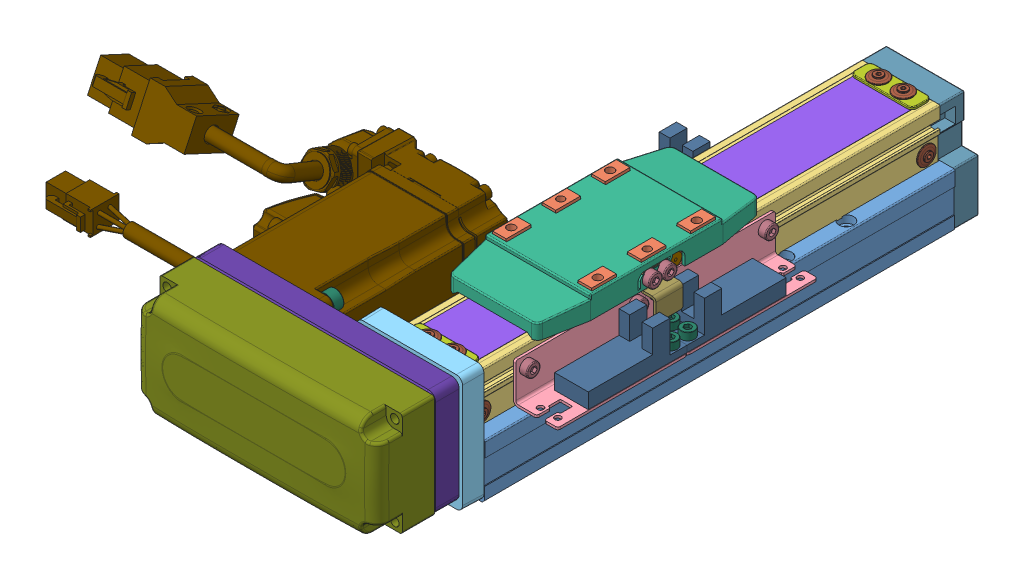
SolidWorks assembly G4-BR-100W, configuration 默认. Lengths in mm.
Overall size (192.63 57.84 250).
59 component instances, 18 part files, 58 mates.
Components (placement in the parent):
- 复件 底座GY4+140^G4-BR-100W-1: 复件 底座GY4+140^G4-BR-100W [默认] at (-6.4941 12.4482 0) x (-1 0 0) z (0 -1 0) size (44 190 22.05) (virtual)
- 复件 滑台G4^G4-BR-100W-1: 复件 滑台G4^G4-BR-100W [默认] at (2.1217 9 -70) x (-1 0 0) z (0 0 -1) size (40 11.99 50) (virtual)
- 复件 侧盖G4+140^G4-BR-100W-1: 复件 侧盖G4+140^G4-BR-100W [默认] at (5.1767 14.25 0) x (-1 0 0) z (0 0 -1) size (8.3 20.5 190) (virtual)
- 复件 304开关座片G5-12^G4-BR-100W-1: 复件 304开关座片G5-12^G4-BR-100W [Default] at (5.9767 22.8 -17.5) x (0 0 -1) z (1 0 0) size (52.5 16 18) (virtual)
- 复件 丝杆座板GY4^G4-BR-100W-1: 复件 丝杆座板GY4^G4-BR-100W [默认] at (-9.9033 24.8518 0) x (-1 0 0) z (0 0 -1) size (43 47.4 8.5) (virtual)
- 复件 滑台盖G4^G4-BR-100W-1: 复件 滑台盖G4^G4-BR-100W [默认] at (-9.9033 42.1 -115) x (0 0 1) z (0 -1 0) size (90 42.6 9) (virtual)
- 复件 304钢带压片G4^G4-BR-100W-1: 复件 304钢带压片G4^G4-BR-100W [默认] at (-9.9033 41.6 -186) x (-1 0 0) z (0 0 -1) size (25 1 8) (virtual)
- 复件 钢带G4+140^G4-BR-100W-1: 复件 钢带G4+140^G4-BR-100W [Default] at (-20.8433 41.5 -581.114) x (0 0 -1) z (0 1 0) size (190 23.5 0.1) (virtual)
- 复件 304钢带压片G4^G4-BR-100W-2: 复件 304钢带压片G4^G4-BR-100W [默认] at (-9.9033 41.6 -4) x (-1 0 0) z (0 0 -1) size (25 1 8) (virtual)
- 复件 弹子油杯D5x5.5^G4-BR-100W-1: 复件 弹子油杯D5x5.5^G4-BR-100W [默认] at (-30.3783 45.5 -78.5) x (0 0.72753 0.686076) z (1 0 0) size (5 5 5.73) (virtual)
- 复件 弹子油杯D5x5.5^G4-BR-100W-2: 复件 弹子油杯D5x5.5^G4-BR-100W [默认] at (10.6217 45.5 -78.5) x (0 0.972647 -0.232289) z (-1 0 0) size (5 5 5.73) (virtual)
- 复件 光电开关EE-SX674^G4-BR-100W-1: 复件 光电开关EE-SX674^G4-BR-100W [默认] at (10.1767 23.8 -30) x (0 0 -1) z (1 0 0) size (40 15.5 13.6) (virtual)
- 复件 不锈钢内六角定制螺丝M3X7^G4-BR-100W-1: 复件 不锈钢内六角定制螺丝M3X7^G4-BR-100W [默认] at (-4.9033 42.9733 -4) x (0.724639 0 -0.689128) z (0 -1 0) size (7.67 7.67 6.5) (virtual)
- 复件 不锈钢内六角定制螺丝M3X7^G4-BR-100W-2: 复件 不锈钢内六角定制螺丝M3X7^G4-BR-100W [默认] at (-14.9033 42.9733 -4) x (0.264221 0 -0.964462) z (0 -1 0) size (7.67 7.67 6.5) (virtual)
- 复件 不锈钢内六角定制螺丝M3X7^G4-BR-100W-3: 复件 不锈钢内六角定制螺丝M3X7^G4-BR-100W [默认] at (-4.9033 42.9733 -186) x (-0.045987 0 0.998942) z (0 -1 0) size (7.67 7.67 6.5) (virtual)
- 复件 不锈钢内六角定制螺丝M3X7^G4-BR-100W-4: 复件 不锈钢内六角定制螺丝M3X7^G4-BR-100W [默认] at (-14.9033 42.9733 -186) x (0.70866 0 0.705551) z (0 -1 0) size (7.67 7.67 6.5) (virtual)
- 复件 不锈钢内六角定制螺丝M3X7^G4-BR-100W-5: 复件 不锈钢内六角定制螺丝M3X7^G4-BR-100W [默认] at (5.55 26.15 -5) x (0 0.645926 0.7634) z (-1 0 0) size (7.67 7.67 6.5) (virtual)
- 复件 不锈钢内六角定制螺丝M3X7^G4-BR-100W-6: 复件 不锈钢内六角定制螺丝M3X7^G4-BR-100W [默认] at (5.55 26.15 -185) x (0 0.430934 0.902383) z (-1 0 0) size (7.67 7.67 6.5) (virtual)
- 复件 不锈钢内六角定制螺丝M3X7^G4-BR-100W-7: 复件 不锈钢内六角定制螺丝M3X7^G4-BR-100W [默认] at (-25.3602 26.15 -185) x (0 -0.999999 -0.001479) z (1 0 0) size (7.67 7.67 6.5) (virtual)
- 复件 不锈钢内六角定制螺丝M3X7^G4-BR-100W-8: 复件 不锈钢内六角定制螺丝M3X7^G4-BR-100W [默认] at (-25.3565 26.15 -5) x (0 -1 0) z (1 0 0) size (7.67 7.67 6.5) (virtual)
- 复件 304感应片G5^G4-BR-100W-1: 复件 304感应片G5^G4-BR-100W [默认] at (15.6217 33 -75.5) x (0 1 0) z (0 0 1) size (15 6.5 11) (virtual)
- hexagon socket head cap screws gb-32: hexagon socket head cap screws gb [GB_FASTENER_SCREWS_HSHCS M3X6-N] at (14.1217 45.5 -73) x (-1 0 0) z (0 -0.928252 -0.371951) size (9 5.5 5.5)
- 复件 光电开关EE-SX674^G4-BR-100W-15: 复件 光电开关EE-SX674^G4-BR-100W [默认] at (23.7767 23.8 -110) x (0 0 1) z (-1 0 0) size (40 15.5 13.6) (virtual)
- 复件 304开关座片G5-12^G4-BR-100W-11: 复件 304开关座片G5-12^G4-BR-100W [Default] at (5.9767 22.8 -70) x (0 0 -1) z (1 0 0) size (52.5 16 18) (virtual)
- 复件 304开关座片G5-12^G4-BR-100W-10: 复件 304开关座片G5-12^G4-BR-100W [Default] at (5.9767 22.8 -87.5) x (0 0 -1) z (1 0 0) size (52.5 16 18) (hidden, virtual)
- 复件 轴承端盖G4(机加件)^G4-BR-100W-1: 复件 轴承端盖G4(机加件)^G4-BR-100W [默认] at (-9.9033 11.9 -190) x (0 0 -1) z (1 0 0) size (10 40.8 43) (virtual)
- hexagon socket head cap screws gb-33: hexagon socket head cap screws gb [GB_FASTENER_SCREWS_HSHCS M3X6-N] at (14.1217 45.5 -67) x (-1 0 0) z (0 -0.928252 -0.371951) size (9 5.5 5.5)
- hexagon socket head cap screws gb-34: hexagon socket head cap screws gb [GB_FASTENER_SCREWS_HSHCS M3X6-N] at (-33.8783 45.5 -73) x (1 0 0) z (0 0.928252 0.371951) size (9 5.5 5.5)
- hexagon socket head cap screws gb-35: hexagon socket head cap screws gb [GB_FASTENER_SCREWS_HSHCS M3X6-N] at (-33.8783 45.5 -67) x (1 0 0) z (0 0.928252 0.371951) size (9 5.5 5.5)
- 复件 侧盖G4+140^G4-BR-100W-5: 复件 侧盖G4+140^G4-BR-100W [默认] at (-24.9833 14.25 -190) size (8.3 20.5 190) (virtual)
- 复件 光电开关EE-SX674^G4-BR-100W-14: 复件 光电开关EE-SX674^G4-BR-100W [默认] at (10.1767 23.8 -100) x (0 0 -1) z (1 0 0) size (40 15.5 13.6) (hidden, virtual)
- 复件 光电开关EE-SX674^G4-BR-100W-16: 复件 光电开关EE-SX674^G4-BR-100W [默认] at (-43.5833 23.8 -100) x (0 0 -1) z (1 0 0) size (40 15.5 13.6) (virtual)
- 复件 304开关座片G5-12^G4-BR-100W-14: 复件 304开关座片G5-12^G4-BR-100W [Default] at (-25.7833 22.8 -140) x (0 0 1) z (-1 0 0) size (52.5 16 18) (virtual)
- 复件 304感应片G5^G4-BR-100W-4: 复件 304感应片G5^G4-BR-100W [默认] at (-35.3783 33 -64.5) x (0 1 0) z (0 0 -1) size (15 6.5 11) (virtual)
- hexagon socket head cap screws gb-36: hexagon socket head cap screws gb [GB_FASTENER_SCREWS_HSHCS M3X6-N] at (-26.4033 5.05 -199.6) x (0 0 1) z (-0.891634 -0.452757 0) size (9 5.5 5.5)
- hexagon socket head cap screws gb-37: hexagon socket head cap screws gb [GB_FASTENER_SCREWS_HSHCS M3X6-N] at (6.5967 5.05 -199.6) x (0 0 1) z (-0.891634 -0.452757 0) size (9 5.5 5.5)
- hexagon socket head cap screws gb-38: hexagon socket head cap screws gb [GB_FASTENER_SCREWS_HSHCS M3X6-N] at (-26.4033 18.05 -199.6) x (0 0 1) z (-0.891634 -0.452757 0) size (9 5.5 5.5)
- hexagon socket head cap screws gb-39: hexagon socket head cap screws gb [GB_FASTENER_SCREWS_HSHCS M3X6-N] at (6.5967 18.05 -199.6) x (0 0 1) z (-0.891634 -0.452757 0) size (9 5.5 5.5)
- hexagon socket head cap screws gb-41: hexagon socket head cap screws gb [GB_FASTENER_SCREWS_HSHCS M3X6-N] at (9.9767 34.8 -21.75) x (-1 0 0) z (0 -0.928252 -0.371951) size (9 5.5 5.5)
- hexagon socket head cap screws gb-42: hexagon socket head cap screws gb [GB_FASTENER_SCREWS_HSHCS M3X6-N] at (9.9767 34.8 -65.75) x (-1 0 0) z (0 -0.928252 -0.371951) size (9 5.5 5.5)
- hexagon socket head cap screws gb-43: hexagon socket head cap screws gb [GB_FASTENER_SCREWS_HSHCS M3X6-N] at (9.9767 34.8 -74.25) x (-1 0 0) z (0 0.928252 -0.371951) size (9 5.5 5.5)
- hexagon socket head cap screws gb-44: hexagon socket head cap screws gb [GB_FASTENER_SCREWS_HSHCS M3X6-N] at (9.9767 34.8 -118.25) x (-1 0 0) z (0 0.928252 -0.371951) size (9 5.5 5.5)
- hexagon socket head cap screws gb-45: hexagon socket head cap screws gb [GB_FASTENER_SCREWS_HSHCS M3X6-N] at (9.9767 34.8 -91.75) x (-1 0 0) z (0 -0.928252 -0.371951) size (9 5.5 5.5) (hidden)
- hexagon socket head cap screws gb-46: hexagon socket head cap screws gb [GB_FASTENER_SCREWS_HSHCS M3X6-N] at (9.9767 34.8 -135.75) x (-1 0 0) z (0 -0.928252 -0.371951) size (9 5.5 5.5) (hidden)
- hexagon socket head cap screws gb-47: hexagon socket head cap screws gb [GB_FASTENER_SCREWS_HSHCS M3X6-N] at (-29.7833 34.8 -135.75) x (1 0 0) z (0 0.928252 0.371951) size (9 5.5 5.5)
- hexagon socket head cap screws gb-48: hexagon socket head cap screws gb [GB_FASTENER_SCREWS_HSHCS M3X6-N] at (-29.7833 34.8 -91.75) x (1 0 0) z (0 0.928252 0.371951) size (9 5.5 5.5)
- socket head cap screw_iso-2: socket head cap screw_iso [ISO 4762 M3 x 5 --- 5N] at (13.4767 29.4 -66.5) x (0 -1 0) z (0 0 1) size (8 5.5 5.5)
- socket head cap screw_iso-3: socket head cap screw_iso [ISO 4762 M3 x 5 --- 5N] at (20.4767 29.4 -66.5) x (0 -1 0) z (0 0 1) size (8 5.5 5.5)
- socket head cap screw_iso-5: socket head cap screw_iso [ISO 4762 M4 x 12 --- 12N] at (-48.8898 41.2635 -0.5) x (0 0 1) z (-0.923728 -0.383049 0) size (16 7 7)
- socket head cap screw_iso-6: socket head cap screw_iso [ISO 4762 M4 x 12 --- 12N] at (-81.4167 8.7365 -0.5) x (0 0 1) z (-0.988061 -0.154063 0) size (16 7 7)
- socket head cap screw_iso-7: socket head cap screw_iso [ISO 4762 M3 x 5 --- 5N] at (20.4767 29.4 -73.5) x (0 -1 0) z (0 0 1) size (8 5.5 5.5)
- socket head cap screw_iso-8: socket head cap screw_iso [ISO 4762 M3 x 5 --- 5N] at (13.4767 29.4 -73.5) x (0 -1 0) z (0 0 1) size (8 5.5 5.5)
- socket head cap screw_iso-9: socket head cap screw_iso [ISO 4762 M3 x 5 --- 5N] at (13.4767 29.4 -136.5) x (0 -1 0) z (0 0 1) size (8 5.5 5.5) (hidden)
- socket head cap screw_iso-10: socket head cap screw_iso [ISO 4762 M3 x 5 --- 5N] at (20.4767 29.4 -136.5) x (0 -1 0) z (0 0 1) size (8 5.5 5.5) (hidden)
- socket head cap screw_iso-11: socket head cap screw_iso [ISO 4762 M3 x 5 --- 5N] at (-33.2833 29.4 -136.5) x (0 -1 0) z (0 0 -1) size (8 5.5 5.5)
- socket head cap screw_iso-12: socket head cap screw_iso [ISO 4762 M3 x 5 --- 5N] at (-40.2833 29.4 -136.5) x (0 -1 0) z (0 0 -1) size (8 5.5 5.5)
- 复件 同步轮罩壳G4^G4-BR-100W-1: 复件 同步轮罩壳G4^G4-BR-100W [默认] at (-38.9033 25 41.5) x (1 0 0) z (0 1 0) size (98.56 24.45 42.56) (virtual)
- 复件 电机板G4-BLRM-P38^G4-BR-100W-1: 复件 电机板G4-BLRM-P38^G4-BR-100W [Default] at (-38.9033 25 -4.5) x (0 0 -1) z (0 -1 0) size (10 98 43) (virtual)
- 复件 台达100W电机ECM-B3L-C20401RS1^G4-BR-100W-1: 复件 台达100W电机ECM-B3L-C20401RS1^G4-BR-100W [Default] at (-65.1533 25 3.5) x (0 1 0) z (0 0 1) size (53.15 124.71 102.71) (virtual)
Mates (geometry in assembly coordinates):
- 重合86: coincident: plane of 复件 滑台G4^G4-BR-100W-1 through (-29.8783 50 -55) normal (0 1 0); plane of 复件 滑台盖G4^G4-BR-100W-1 through (-31.2033 50 -96.25) normal (0 -1 0)
- 同心50: concentric: cylinder of 复件 滑台G4^G4-BR-100W-1 through (-29.8783 45.5 -78.5) axis (-1 0 0) radius 2.5; cylinder of 复件 弹子油杯D5x5.5^G4-BR-100W-1 through (-24.8783 45.5 -78.5) axis (-1 0 0) radius 2.5
- 重合98: coincident: plane of 复件 滑台G4^G4-BR-100W-1 through (-24.8783 45.5 -78.5) normal (-1 0 0); circle of 复件 弹子油杯D5x5.5^G4-BR-100W-1
- 同心51: concentric: cylinder of 复件 滑台G4^G4-BR-100W-1 through (10.1217 45.5 -78.5) axis (1 0 0) radius 2.5; cylinder of 复件 弹子油杯D5x5.5^G4-BR-100W-2 through (5.1217 45.5 -78.5) axis (1 0 0) radius 2.5
- 重合99: coincident: plane of 复件 滑台G4^G4-BR-100W-1 through (5.1217 45.5 -78.5) normal (1 0 0); circle of 复件 弹子油杯D5x5.5^G4-BR-100W-2
- 重合127: coincident: plane of 复件 304钢带压片G4^G4-BR-100W-1 through (0.5967 42.6 -184) normal (0 1 0); circle of 复件 不锈钢内六角定制螺丝M3X7^G4-BR-100W-3
- 重合128: coincident: plane of 复件 304钢带压片G4^G4-BR-100W-1 through (0.5967 42.6 -184) normal (0 1 0); circle of 复件 不锈钢内六角定制螺丝M3X7^G4-BR-100W-4
- 同心86: concentric: circle of 复件 侧盖G4+140^G4-BR-100W-1; cylinder of 复件 不锈钢内六角定制螺丝M3X7^G4-BR-100W-6 through (0.07 26.15 -185) axis (1 0 0) radius 1.5
- 重合133: coincident: plane of 复件 侧盖G4+140^G4-BR-100W-1 through (5.1767 30.4257 -190) normal (1 0 0); circle of 复件 不锈钢内六角定制螺丝M3X7^G4-BR-100W-6
- 重合150: coincident: plane of 复件 滑台G4^G4-BR-100W-1 through (10.1217 42.5 -95) normal (1 0 0); plane of 复件 304感应片G5^G4-BR-100W-1 through (10.1217 41 -64.5) normal (-1 0 0)
- 同心103: concentric: cylinder of 复件 滑台G4^G4-BR-100W-1 through (10.1217 45.5 -73) axis (1 0 0) radius 1.25; cylinder of 复件 304感应片G5^G4-BR-100W-1 through (10.1217 45.5 -73) axis (-1 0 0) radius 1.7
- 同心104: concentric: cylinder of 复件 滑台G4^G4-BR-100W-1 through (10.1217 45.5 -67) axis (1 0 0) radius 1.25; cylinder of 复件 304感应片G5^G4-BR-100W-1 through (10.1217 45.5 -67) axis (-1 0 0) radius 1.7
- 同心105: concentric: cylinder of 复件 滑台G4^G4-BR-100W-1 through (10.1217 45.5 -73) axis (1 0 0) radius 1.25; cylinder of hexagon socket head cap screws gb-32 through (5.1217 45.5 -73) axis (1 0 0) radius 1.5
- 重合154: coincident: plane of 复件 304感应片G5^G4-BR-100W-1 through (11.1217 41 -64.5) normal (1 0 0); plane of hexagon socket head cap screws gb-32 through (11.1217 45.5 -73) normal (-1 0 0)
- 宽度8: width: plane of 复件 滑台盖G4^G4-BR-100W-1 through (-30.1033 42.1 -75.05) normal (0 0 1); plane of 复件 滑台盖G4^G4-BR-100W-1 through (-30.1033 42.1 -64.95) normal (0 0 -1); plane of 复件 滑台G4^G4-BR-100W-1 through (-29.8783 52 -65) normal (0 0 1); plane of 复件 滑台G4^G4-BR-100W-1 through (-29.8783 52 -75) normal (0 0 -1)
- 宽度9: width: plane of 复件 滑台G4^G4-BR-100W-1 through (-24.3783 48 -95) normal (1 0 0); plane of 复件 滑台G4^G4-BR-100W-1 through (-29.8783 52 -95) normal (-1 0 0); plane of 复件 滑台盖G4^G4-BR-100W-1 through (-24.1533 42.1 -64.95) normal (-1 0 0); plane of 复件 滑台盖G4^G4-BR-100W-1 through (-30.1033 50.6 -96.25) normal (1 0 0)
- 重合171: coincident: plane of 复件 底座GY4+140^G4-BR-100W-1 through (-31.4033 21.55 -190) normal (0 0 -1); plane of 复件 轴承端盖G4(机加件)^G4-BR-100W-1 through (-9.9033 11.9 -190) normal (0 0 1)
- 宽度10: width: plane of 复件 底座GY4+140^G4-BR-100W-1 through (12.0967 21.55 -190) normal (1 0 0); plane of 复件 底座GY4+140^G4-BR-100W-1 through (-31.9033 16.05 -190) normal (-1 0 0); plane of 复件 滑台盖G4^G4-BR-100W-1 through (-31.2033 50.6 -96.25) normal (-1 0 0); plane of 复件 滑台盖G4^G4-BR-100W-1 through (11.3967 50.6 -96.25) normal (1 0 0)
- 距离4: distance = 52 mm: plane of 复件 滑台G4^G4-BR-100W-1 through (-24.3783 52 -95) normal (0 1 0); plane of 复件 底座GY4+140^G4-BR-100W-1 through (15.1408 0 0) normal (0 -1 0)
- 重合187: coincident: plane of 复件 底座GY4+140^G4-BR-100W-1 through (-31.4033 6.05 -190) normal (-1 0 0); plane of 复件 轴承端盖G4(机加件)^G4-BR-100W-1 through (-31.4033 11.9 -200) normal (-1 0 0)
- 同心117: concentric: cylinder of 复件 不锈钢内六角定制螺丝M3X7^G4-BR-100W-7 through (-19.8802 26.15 -185) axis (-1 0 0) radius 1.5; cylinder of 复件 侧盖G4+140^G4-BR-100W-5 through (-24.9833 26.15 -185) axis (-1 0 0) radius 1.5
- 相切3: tangent: torus of 复件 不锈钢内六角定制螺丝M3X7^G4-BR-100W-7; plane of 复件 侧盖G4+140^G4-BR-100W-5 through (-24.9833 30.4257 0) normal (-1 0 0)
- 重合189: coincident: plane of 复件 304钢带压片G4^G4-BR-100W-1 through (0.5967 41.6 -184) normal (0 -1 0); plane of 复件 钢带G4+140^G4-BR-100W-1 through (-20.8433 41.6 -581.114) normal (0 1 0)
- 同心118: concentric: cylinder of 复件 304钢带压片G4^G4-BR-100W-1 through (-4.9033 42.6 -186) axis (0 -1 0) radius 1.65; cylinder of 复件 不锈钢内六角定制螺丝M3X7^G4-BR-100W-3 through (-4.9033 37.4933 -186) axis (0 1 0) radius 1.5
- 同心119: concentric: cylinder of 复件 304钢带压片G4^G4-BR-100W-1 through (-14.9033 42.6 -186) axis (0 -1 0) radius 1.65; cylinder of 复件 不锈钢内六角定制螺丝M3X7^G4-BR-100W-4 through (-14.9033 37.4933 -186) axis (0 1 0) radius 1.5
- 重合190: coincident: plane of 复件 304钢带压片G4^G4-BR-100W-1 through (0.5967 42.6 -190) normal (0 0 -1); plane of 复件 轴承端盖G4(机加件)^G4-BR-100W-1 through (-9.9033 11.9 -190) normal (0 0 1)
- 宽度11: width: plane of 复件 304钢带压片G4^G4-BR-100W-1 through (-22.4033 42.6 -184) normal (-1 0 0); plane of 复件 304钢带压片G4^G4-BR-100W-1 through (2.5967 42.6 -184) normal (1 0 0); plane of 复件 侧盖G4+140^G4-BR-100W-1 through (5.9767 41.05 -190) normal (1 0 0); plane of 复件 侧盖G4+140^G4-BR-100W-5 through (-25.7833 41.05 0) normal (-1 0 0)
- 重合191: coincident: plane of 复件 轴承端盖G4(机加件)^G4-BR-100W-1 through (-26.4033 6.75 -196.6) normal (0 0 -1); plane of hexagon socket head cap screws gb-36 through (-26.4033 5.05 -196.6) normal (0 0 1)
- 同心121: concentric: cylinder of 复件 轴承端盖G4(机加件)^G4-BR-100W-1 through (-26.4033 5.05 -200) axis (0 0 -1) radius 1.7; cylinder of hexagon socket head cap screws gb-36 through (-26.4033 5.05 -190.6) axis (0 0 -1) radius 1.5
- 重合193: coincident: plane of 复件 304开关座片G5-12^G4-BR-100W-1 through (6.9767 40.8 -70) normal (1 0 0); plane of hexagon socket head cap screws gb-41 through (6.9767 34.8 -21.75) normal (-1 0 0)
- 同心123: concentric: cylinder of 复件 304开关座片G5-12^G4-BR-100W-1 through (5.9767 34.8 -21.75) axis (1 0 0) radius 1.6; cylinder of hexagon socket head cap screws gb-41 through (0.9767 34.8 -21.75) axis (1 0 0) radius 1.5
- 同心126: concentric: cylinder of 复件 光电开关EE-SX674^G4-BR-100W-1 through (13.4767 12.8 -66.5) axis (0 1 0) radius 1.75; cylinder of socket head cap screw_iso-2 through (13.4767 61.15 -66.5) axis (0 1 0) radius 2.75
- 重合196: coincident: plane of 复件 光电开关EE-SX674^G4-BR-100W-1 through (23.7767 26.4 -63) normal (0 1 0); plane of socket head cap screw_iso-2 through (16.2267 26.4 -66.5) normal (0 -1 0)
- 同心127: concentric: cylinder of 复件 光电开关EE-SX674^G4-BR-100W-1 through (20.4767 12.8 -66.5) axis (0 1 0) radius 1.75; cylinder of socket head cap screw_iso-3 through (20.4767 61.15 -66.5) axis (0 1 0) radius 2.75
- 重合197: coincident: plane of 复件 光电开关EE-SX674^G4-BR-100W-1 through (23.7767 26.4 -63) normal (0 1 0); plane of socket head cap screw_iso-3 through (23.2267 26.4 -66.5) normal (0 -1 0)
- 重合198: coincident: plane of 复件 丝杆座板GY4^G4-BR-100W-1 through (-9.9033 24.8518 8.5) normal (0 0 1); plane of 复件 电机板G4-BLRM-P38^G4-BR-100W-1 through (-38.9033 25 8.5) normal (0 0 -1)
- 重合199: coincident: plane of 复件 同步轮罩壳G4^G4-BR-100W-1 through (-38.9033 25 18.5) normal (0 0 -1); plane of 复件 电机板G4-BLRM-P38^G4-BR-100W-1 through (-38.9033 25 18.5) normal (0 0 1)
- 同心128: concentric: cylinder of 复件 同步轮罩壳G4^G4-BR-100W-1 through (-84.9033 43 31.5) axis (0 0 1) radius 1.75; cylinder of 复件 电机板G4-BLRM-P38^G4-BR-100W-1 through (-84.9033 43 18.5) axis (0 0 1) radius 1.25
- 同心129: concentric: cylinder of 复件 同步轮罩壳G4^G4-BR-100W-1 through (7.0967 7 31.5) axis (0 0 1) radius 1.75; cylinder of 复件 电机板G4-BLRM-P38^G4-BR-100W-1 through (7.0967 7 18.5) axis (0 0 1) radius 1.25
- 同心130: concentric: cylinder of 复件 丝杆座板GY4^G4-BR-100W-1 through (-9.9033 25 -1.5) axis (0 0 1) radius 9.2036; cylinder of 复件 电机板G4-BLRM-P38^G4-BR-100W-1 through (-9.9033 25 8.5) axis (0 0 1) radius 16
- 平行2: parallel: plane of 复件 底座GY4+140^G4-BR-100W-1 through (15.1408 0 0) normal (0 -1 0); plane of 复件 电机板G4-BLRM-P38^G4-BR-100W-1 through (-87.9033 46.5 18.5) normal (0 1 0)
- 同心131: concentric: cylinder of 复件 电机板G4-BLRM-P38^G4-BR-100W-1 through (-65.1533 25 8.5) axis (0 0 1) radius 15; cylinder of 复件 台达100W电机ECM-B3L-C20401RS1^G4-BR-100W-1 through (-65.1533 25 8.5) axis (0 0 1) radius 15
- 重合202: coincident: plane of 复件 电机板G4-BLRM-P38^G4-BR-100W-1 through (-38.9033 25 8.5) normal (0 0 -1); plane of 复件 台达100W电机ECM-B3L-C20401RS1^G4-BR-100W-1 through (-45.1333 4.98 8.5) normal (0 0 1)
- 重合203: coincident: plane of socket head cap screw_iso-5 through (-50.2305 44.4965 3.5) normal (0 0 1); plane of 复件 台达100W电机ECM-B3L-C20401RS1^G4-BR-100W-1 through (-45.7703 37.4715 3.5) normal (0 0 -1)
- 同心135: concentric: cylinder of socket head cap screw_iso-5 through (-48.8898 41.2635 -32.25) axis (0 0 -1) radius 2; cone of 复件 台达100W电机ECM-B3L-C20401RS1^G4-BR-100W-1 through (-48.8898 41.2635 3.5) axis (0 0 -1)
- 重合204: coincident: plane of socket head cap screw_iso-6 through (-81.956 12.1948 3.5) normal (0 0 1); plane of 复件 台达100W电机ECM-B3L-C20401RS1^G4-BR-100W-1 through (-77.6247 5.6171 3.5) normal (0 0 -1)
- 同心136: concentric: cylinder of socket head cap screw_iso-6 through (-81.4167 8.7365 -32.25) axis (0 0 -1) radius 2; cone of 复件 台达100W电机ECM-B3L-C20401RS1^G4-BR-100W-1 through (-81.4167 8.7365 3.5) axis (0 0 -1)
- 平行3: parallel: plane of 复件 电机板G4-BLRM-P38^G4-BR-100W-1 through (-87.9033 46.5 18.5) normal (0 1 0); plane of 复件 台达100W电机ECM-B3L-C20401RS1^G4-BR-100W-1 through (-47.7333 44.75 -49.324) normal (0 1 0)
- 宽度12: width: plane of 复件 光电开关EE-SX674^G4-BR-100W-1 through (23.7767 39.3 -63) normal (0 0 -1); plane of 复件 光电开关EE-SX674^G4-BR-100W-15 through (10.1767 39.3 -77) normal (0 0 1); plane of 复件 304感应片G5^G4-BR-100W-1 through (16.6217 40.5 -64.5) normal (0 0 1); plane of 复件 304感应片G5^G4-BR-100W-1 through (11.1217 42.5 -75.5) normal (0 0 -1)
- 同心137: concentric: cylinder of 复件 304开关座片G5-12^G4-BR-100W-1 through (13.4767 23.8 -66.5) axis (0 1 0) radius 1.25; cylinder of socket head cap screw_iso-2 through (13.4767 61.15 -66.5) axis (0 1 0) radius 2.75
- 同心138: concentric: cylinder of 复件 304开关座片G5-12^G4-BR-100W-1 through (20.4767 23.8 -66.5) axis (0 1 0) radius 1.25; cylinder of socket head cap screw_iso-3 through (20.4767 61.15 -66.5) axis (0 1 0) radius 2.75
- 重合205: coincident: plane of 复件 304开关座片G5-12^G4-BR-100W-1 through (7.9767 23.8 -70) normal (0 1 0); plane of 复件 光电开关EE-SX674^G4-BR-100W-1 through (23.7767 23.8 -70) normal (0 -1 0)
- 宽度13: width: plane of 复件 侧盖G4+140^G4-BR-100W-1 through (5.9767 36.55 -190) normal (0 -1 0); plane of 复件 侧盖G4+140^G4-BR-100W-1 through (5.0767 33.05 -190) normal (0 1 0); cylinder of 复件 304开关座片G5-12^G4-BR-100W-11 through (5.9767 34.8 -118.25) axis (1 0 0) radius 1.6
- 重合206: coincident: plane of 复件 侧盖G4+140^G4-BR-100W-1 through (5.9767 32.95 -190) normal (1 0 0); plane of 复件 304开关座片G5-12^G4-BR-100W-11 through (5.9767 24.8 -122.5) normal (-1 0 0)
- 距离5: distance = 112.5 mm: line of 复件 304开关座片G5-12^G4-BR-100W-1 through (6.9767 37.8 -70) axis (0 -1 0); plane of 复件 同步轮罩壳G4^G4-BR-100W-1 through (-9.9033 25 42.5) normal (0 0 1)
- 宽度14: width: plane of 复件 底座GY4+140^G4-BR-100W-1 through (-31.9033 16.05 -190) normal (-1 0 0); plane of 复件 底座GY4+140^G4-BR-100W-1 through (12.0967 21.55 -190) normal (1 0 0); plane of 复件 丝杆座板GY4^G4-BR-100W-1 through (11.5967 48.0518 0) normal (0.999848 0 0.017452); plane of 复件 丝杆座板GY4^G4-BR-100W-1 through (-31.4033 48.0518 0) normal (-0.999848 0 0.017452)
- 重合208: coincident: plane of 复件 底座GY4+140^G4-BR-100W-1 through (-31.4033 21.55 0) normal (0 0 1); plane of 复件 丝杆座板GY4^G4-BR-100W-1 through (-9.9033 24.8518 0) normal (0 0 -1)
- 距离6: distance = 25 mm: axis of 复件 丝杆座板GY4^G4-BR-100W-1 through (-9.9033 25 0) axis (0 0 1); plane of 复件 底座GY4+140^G4-BR-100W-1 through (15.1408 0 0) normal (0 -1 0)
